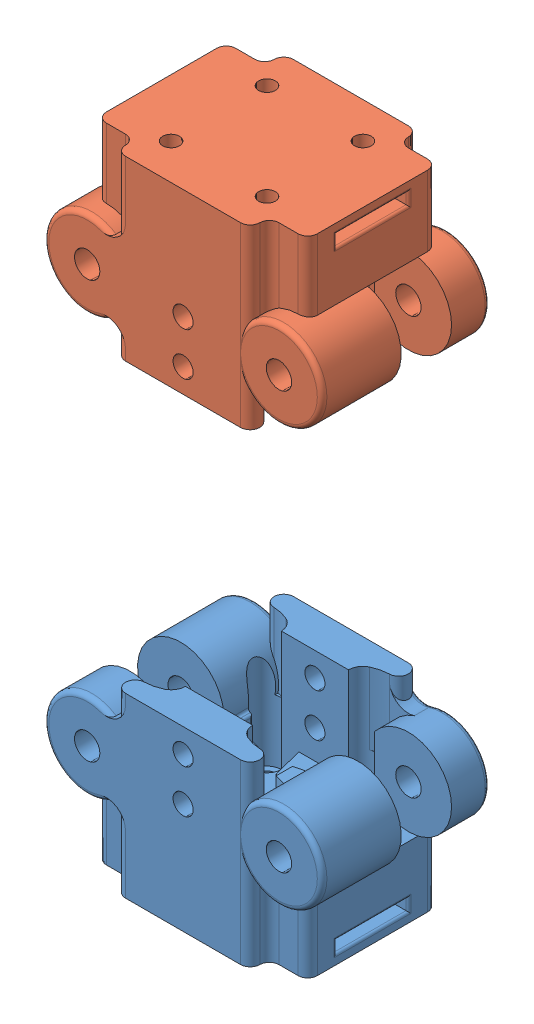
SolidWorks assembly MIRROR_CarriadgeJoint, configuration Default. Lengths in mm.
Overall size (58 134 35.37).
2 component instances, 2 part files, 0 mates.
Components (placement in the parent):
- CarriadgeJoint-1: CarriadgeJoint [Default] at (3.5885 6.979 43.1223) size (58 37 35.37)
- MirrorCarriadgeJoint-2: MirrorCarriadgeJoint [Default] at (3.5885 140.979 43.1223) x (1 0 0) z (0 0 -1) size (58 37 35.37)
